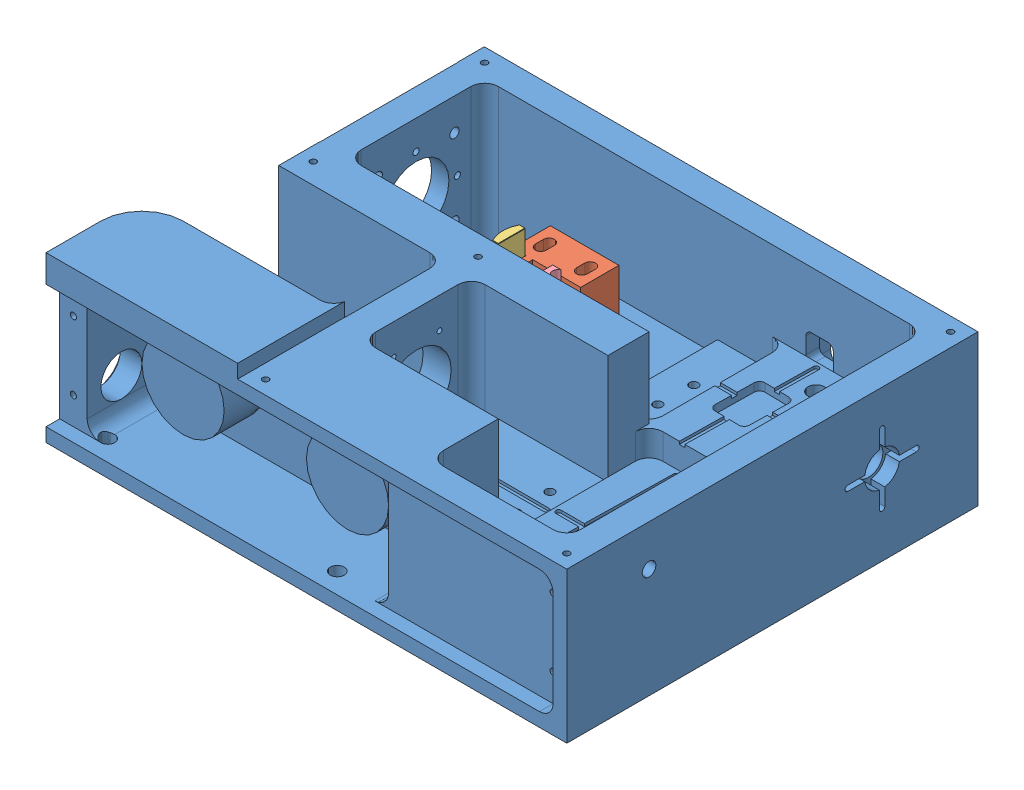
SolidWorks assembly Assem2, configuration Default. Lengths in mm.
Overall size (190 60 150).
6 component instances, 5 part files, 2 mates.
Components (placement in the parent):
- laser_cavity2-1: laser_cavity2 [Default] at (-87.9942 62.2323 144.5875) size (190 60 150)
- telescope_v2_two_part-1: telescope_v2_two_part [Default] at (-4.9972 54.6965 106.4458) size (25 25.3 38)
  - telescope_v2_concave-2: telescope_v2_concave [Default] at (18505.0278 17.5357 11312.7564) size (25 16.5 38)
  - telescope_lens_plate-1: telescope_lens_plate [Default] at (32.0332 32.257 13.9502) x (-1 0 0) z (0 0 -1) size (12 16 10) (hidden)
  - cylindricalconvex_LJ1960L1-B-Solidworks-1: cylindricalconvex_LJ1960L1-B-Solidworks [Default] at (14.4361 36.8357 14.6151) x (0 1 0) z (-1 0 0) size (12 10 3.29)
  - cyl_lens_concave-2: cyl_lens_concave [Default] at (30.6125 35.3109 14.6651) x (0 1 0) z (1 0 0) size (8 4 3.16)
Mates (geometry in assembly coordinates):
- Coincident1: coincident anti-aligned: plane of laser_cavity2-1 through (-87.9942 72.2323 144.5875) normal (0 1 0); plane of telescope_v2_two_part-1/telescope_v2_concave-2 through (18500.0306 72.2323 11419.2022) normal (0 -1 0)
- Concentric1: concentric: cylinder of laser_cavity2-1 through (26.0839 72.2323 109.0109) axis (0 1 0) radius 1.3526; point of telescope_v2_two_part-1/telescope_v2_concave-2
